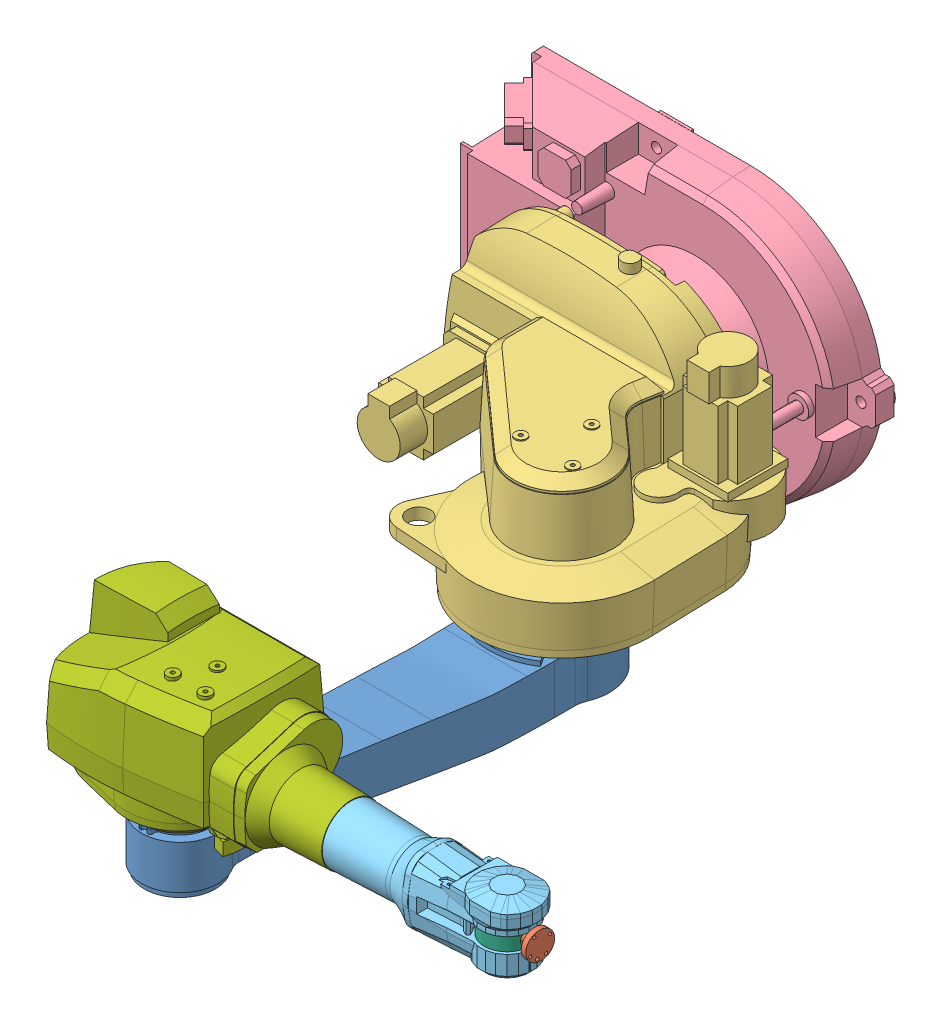
SolidWorks assembly IRB1600_X-145_m2004_rev0_01, configuration Default. Lengths in mm.
Overall size (1198.62 503.44 1294.47).
7 component instances, 7 part files, 21 mates.
Components (placement in the parent):
- IRB1600_X-145_m2004_rev0_01-3-1: IRB1600_X-145_m2004_rev0_01-3 [Default] at (0 -1.5 0) size (189.81 153.68 858.27)
- IRB1600_X-145_m2004_rev0_01-7-1: IRB1600_X-145_m2004_rev0_01-7 [Default] at (19.1473 1144.5368 843.5705) x (0.99814 0 0.060967) z (-0.015299 -0.968004 0.250466) size (65 49.99 49.99)
- IRB1600_X-145_m2004_rev0_01-2-1: IRB1600_X-145_m2004_rev0_01-2 [Default] at origin size (579.28 368.16 527.13)
- IRB1600_X-145_m2004_rev0_01-1-1: IRB1600_X-145_m2004_rev0_01-1 [Default] at origin size (660.28 483.27 171)
- IRB1600_X-145_m2004_rev0_01-5-1: IRB1600_X-145_m2004_rev0_01-5 [Default] at (0 -4.498 2373) x (1 0 0) z (0 0 -1) size (341 125.18 112.07)
- IRB1600_X-145_m2004_rev0_01-6-1: IRB1600_X-145_m2004_rev0_01-6 [Default] at (-70.942 -3.998 2325.0677) x (0.99814 0 0.060967) z (0.060967 0 -0.99814) size (84 47 84)
- IRB1600_X-145_m2004_rev0_01-4-1: IRB1600_X-145_m2004_rev0_01-4 [Default] at (0 -4.502 0) size (489.6 281 243.82)
Mates (geometry in assembly coordinates):
- Coincident2: coordinate: unknown of IRB1600_X-145_m2004_rev0_01-1-1
- Parallel1: parallel aligned: plane of IRB1600_X-145_m2004_rev0_01-1-1 through (0 0 0) normal (0 1 0)
- Parallel2: parallel anti-aligned: plane of IRB1600_X-145_m2004_rev0_01-2-1 through (0 -73.025 124.5) normal (0 0 -1); plane of IRB1600_X-145_m2004_rev0_01-1-1 through (0 42.1137 124.5) normal (0 0 1)
- Concentric1: concentric anti-aligned: cylinder of IRB1600_X-145_m2004_rev0_01-2-1 through (0 0 124.5) axis (0 0 -1) radius 73.025; cylinder of IRB1600_X-145_m2004_rev0_01-1-1 through (0 0 124.5) axis (0 0 1) radius 73
- Coincident7: coincident anti-aligned: plane of IRB1600_X-145_m2004_rev0_01-2-1 through (0 -73.025 124.5) normal (0 0 -1); plane of IRB1600_X-145_m2004_rev0_01-1-1 through (0 42.1137 124.5) normal (0 0 1)
- Parallel3: parallel anti-aligned: plane of IRB1600_X-145_m2004_rev0_01-3-1 through (184.134 -139.5 486.5) normal (0 1 0); plane of IRB1600_X-145_m2004_rev0_01-2-1 through (150 -139.5 576.5) normal (0 -1 0)
- Concentric2: concentric anti-aligned: cylinder of IRB1600_X-145_m2004_rev0_01-3-1 through (150 -40.5051 486.5) axis (0 -1 0) radius 35; cylinder of IRB1600_X-145_m2004_rev0_01-2-1 through (150 -143 486.5) axis (0 1 0) radius 35
- Coincident9: coincident anti-aligned: plane of IRB1600_X-145_m2004_rev0_01-3-1 through (184.134 -139.5 486.5) normal (0 1 0); plane of IRB1600_X-145_m2004_rev0_01-2-1 through (150 -139.5 576.5) normal (0 -1 0)
- Parallel4: parallel anti-aligned: plane of IRB1600_X-145_m2004_rev0_01-3-1 through (150 -116.5 1251.5) normal (0 1 0); plane of IRB1600_X-145_m2004_rev0_01-4-1 through (174.8137 -119.502 1233.8976) normal (0 -1 0)
- Concentric4: concentric anti-aligned: cylinder of IRB1600_X-145_m2004_rev0_01-3-1 through (150 -26.6472 1186.5) axis (0 -1 0) radius 30; cylinder of IRB1600_X-145_m2004_rev0_01-4-1 through (150 -119.502 1186.5) axis (0 1 0) radius 30.5359
- Coincident12: coincident anti-aligned: plane of IRB1600_X-145_m2004_rev0_01-3-1 through (179.134 -111.5 1186.5) normal (0 1 0); plane of IRB1600_X-145_m2004_rev0_01-4-1 through (150 -111.5 1118.5) normal (0 -1 0)
- Coincident13: coincident anti-aligned: plane of IRB1600_X-145_m2004_rev0_01-5-1 through (464 -4.5 1186.5) normal (-1 0 0); plane of IRB1600_X-145_m2004_rev0_01-4-1 through (464 -4.5 1186.5) normal (1 0 0)
- Parallel5: parallel anti-aligned: plane of IRB1600_X-145_m2004_rev0_01-5-1 through (464 -4.5 1186.5) normal (-1 0 0); plane of IRB1600_X-145_m2004_rev0_01-4-1 through (464 -4.5 1186.5) normal (1 0 0)
- Concentric5: concentric aligned: cone of IRB1600_X-145_m2004_rev0_01-5-1 through (464 -4.5 1186.5) axis (1 0 0); cone of IRB1600_X-145_m2004_rev0_01-4-1 through (371.121 -4.5 1186.5) axis (1 0 0)
- Parallel7: parallel anti-aligned: plane of IRB1600_X-145_m2004_rev0_01-5-1 through (711 9.5 1216.5) normal (0 -1 0); plane of IRB1600_X-145_m2004_rev0_01-6-1 through (750 19.5 1186.5) normal (0 1 0)
- Concentric6: concentric aligned: cylinder of IRB1600_X-145_m2004_rev0_01-5-1 through (750 -24.5 1186.5) axis (0 1 0) radius 15; cylinder of IRB1600_X-145_m2004_rev0_01-6-1 through (750 -4 1186.5) axis (0 1 0) radius 33
- Coincident20: coincident anti-aligned: plane of IRB1600_X-145_m2004_rev0_01-5-1 through (711 -18.5 1216.5) normal (0 1 0); plane of IRB1600_X-145_m2004_rev0_01-6-1 through (791.9219 -18.5 1189.0606) normal (0 -1 0)
- Concentric7: concentric anti-aligned: cylinder of IRB1600_X-145_m2004_rev0_01-7-1 through (749.6003 -4 1186.4756) axis (-0.99814 0 -0.060967) radius 8.5; cylinder of IRB1600_X-145_m2004_rev0_01-6-1 through (707.5751 -4 1183.9087) axis (0.99814 0 0.060967) radius 12.5
- Lock2: lock: unknown of IRB1600_X-145_m2004_rev0_01-7-1; unknown of IRB1600_X-145_m2004_rev0_01-6-1
- Coincident28: coincident aligned: plane of IRB1600_X-145_m2004_rev0_01-4-1 through (0 -4.502 0) normal (1 0 0)
- Parallel11: parallel anti-aligned: plane of IRB1600_X-145_m2004_rev0_01-5-1 through (0 -4.498 2373) normal (0 -1 0)
